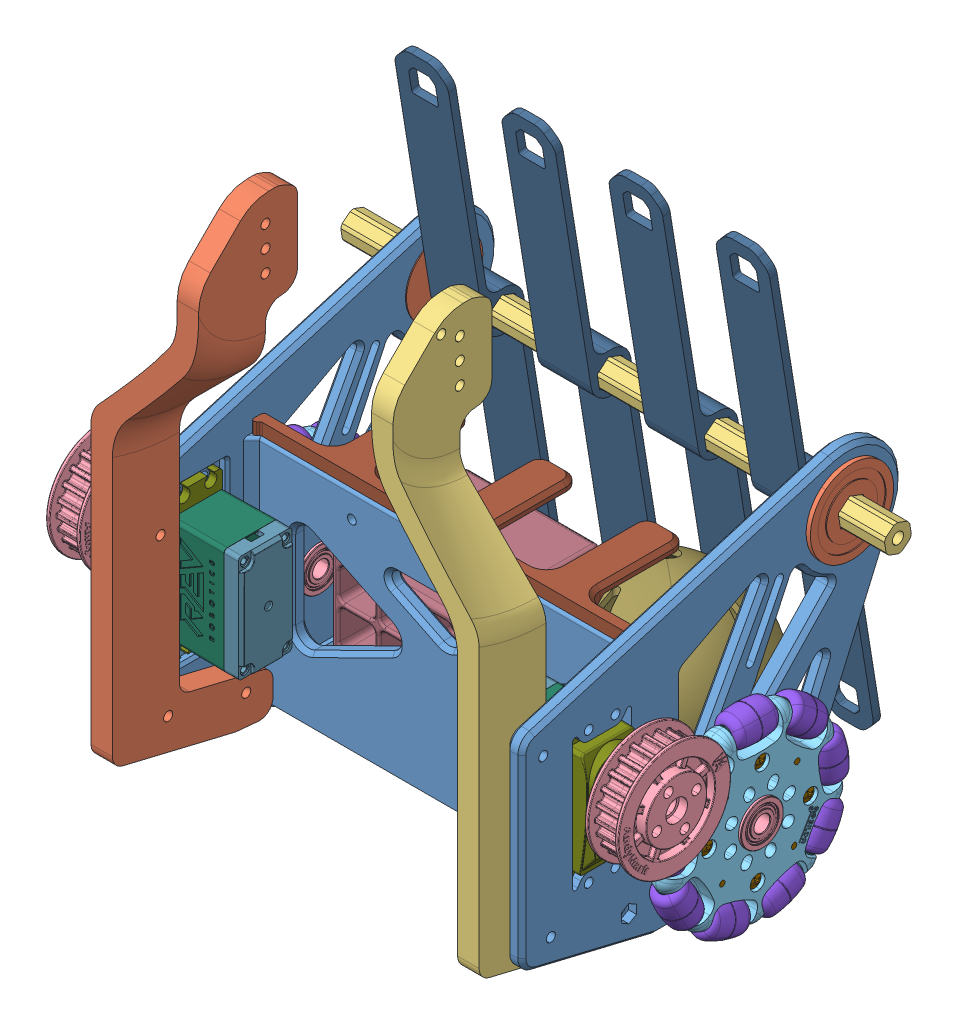
SolidWorks assembly Intake2, configuration Default. Lengths in mm.
Overall size (212.71 218.44 158.53).
113 component instances, 22 part files, 75 mates.
Components (placement in the parent):
- IntakeWide-1: IntakeWide [Default] at (-43.2378 29.5162 123.384) size (157 122.29 142.09)
- 0_375_Hex_ID_x_1_125_OD_x_0_313_WD_Flanged_Bearing_217-2735 (1).step-1: 0_375_Hex_ID_x_1_125_OD_x_0_313_WD_Flanged_Bearing_217-2735 (1).step [Default] at (101.4122 125.5162 108.384) x (0 0.631718 -0.775198) z (0 -0.775198 -0.631718) size (31.12 7.94 31.12)
- 0_375_Hex_ID_x_1_125_OD_x_0_313_WD_Flanged_Bearing_217-2735 (1).step-2: 0_375_Hex_ID_x_1_125_OD_x_0_313_WD_Flanged_Bearing_217-2735 (1).step [Default] at (-42.8878 125.5162 108.384) x (0 0.9872 0.159485) z (0 -0.159485 0.9872) size (31.12 7.94 31.12)
- 375Hex13.33in-1: 375Hex13.33in [Default] at (-330.7015 125.5132 108.3759) x (0 0.631718 -0.775198) z (-1 0 0) size (10.24 9.53 203.2)
- 1601-0014-0006.step-1: 1601-0014-0006.step [Default] at (105.8122 54.5162 155.184) x (0 -0.381849 0.924225) z (0 -0.924225 -0.381849) size (15.95 5 15.95)
- 1601-0014-0006.step-2: 1601-0014-0006.step [Default] at (-47.2878 54.5162 155.184) x (0 -1 0) z (0 0 1) size (15.95 5 15.95)
- 3604-0014-0072 assembly.STEP-1: 3604-0014-0072 assembly.STEP [Default] at (98.0385 38.1974 184.2388) x (0 -0.339821 0.94049) z (0 0.94049 0.339821) size (78.59 16.98 77.39)
  - 3604-0014-0072 wheel half.STEP-1: 3604-0014-0072 wheel half.STEP [Default] at (-32.8712 13.6737 5.4742) size (67.84 5 66.97)
  - 3604-0014-0072 wheel half.STEP-2: 3604-0014-0072 wheel half.STEP [Default] at (-32.8712 23.6737 5.4742) x (-1 0 0) z (0 0 1) size (67.84 5 66.97)
  - 3604-0014-0072 bushing.STEP-1: 3604-0014-0072 bushing.STEP [Default] at (-52.1548 18.6737 -17.5071) x (-0.130318 0.979233 -0.155307) z (-0.766044 0 0.642788) size (5.61 5.61 17.1)
  - 3604-0014-0072 shaft.STEP-1: 3604-0014-0072 shaft.STEP [Default] at (-60.0068 18.6737 -10.9185) x (0.629069 0.205497 0.749695) z (-0.132091 0.978658 -0.15742) size (3.17 20.5 3.17)
  - 3604-0014-0072 roller.STEP-1: 3604-0014-0072 roller.STEP [Default] at (-52.1548 18.6737 -17.5071) x (-0.385664 0.800009 -0.459617) z (-0.766044 0 0.642788) size (12.13 12.13 16)
  - 3604-0014-0072 shaft.STEP-2: 3604-0014-0072 shaft.STEP [Default] at (-43.1212 18.6737 -24.5258) x (0 0.205497 0.978658) z (0 0.978658 -0.205497) size (3.17 20.5 3.17)
  - 3604-0014-0072 shaft.STEP-3: 3604-0014-0072 shaft.STEP [Default] at (-21.4395 18.6737 -24.0957) x (-0.629069 0.205497 0.749695) z (0.132091 0.978658 -0.15742) size (3.17 20.5 3.17)
  - 3604-0014-0072 shaft.STEP-4: 3604-0014-0072 shaft.STEP [Default] at (-5.1069 18.6737 -9.8295) x (-0.96379 0.205497 0.169942) z (0.202375 0.978658 -0.035684) size (3.17 20.5 3.17)
  - 3604-0014-0072 shaft.STEP-5: 3604-0014-0072 shaft.STEP [Default] at (-1.7654 18.6737 11.5975) x (-0.847543 0.205497 -0.489329) z (0.177965 0.978658 0.102748) size (3.17 20.5 3.17)
  - 3604-0014-0072 shaft.STEP-6: 3604-0014-0072 shaft.STEP [Default] at (-12.9787 18.6737 30.1593) x (-0.334721 0.205497 -0.919638) z (0.070284 0.978658 0.193104) size (3.17 20.5 3.17)
  - 3604-0014-0072 shaft.STEP-7: 3604-0014-0072 shaft.STEP [Default] at (-33.4999 18.6737 37.1707) x (0.334721 0.205497 -0.919638) z (-0.070284 0.978658 0.193104) size (3.17 20.5 3.17)
  - 3604-0014-0072 shaft.STEP-8: 3604-0014-0072 shaft.STEP [Default] at (-53.727 18.6737 29.351) x (0.847543 0.205497 -0.489329) z (-0.177965 0.978658 0.102748) size (3.17 20.5 3.17)
  - 3604-0014-0072 shaft.STEP-9: 3604-0014-0072 shaft.STEP [Default] at (-64.1953 18.6737 10.3591) x (0.96379 0.205497 0.169942) z (-0.202375 0.978658 -0.035684) size (3.17 20.5 3.17)
  - 3604-0014-0072 bushing.STEP-2: 3604-0014-0072 bushing.STEP [Default] at (-32.8712 18.6737 -24.5258) x (0 0.979233 -0.202739) z (-1 0 0) size (5.61 5.61 17.1)
  - 3604-0014-0072 bushing.STEP-3: 3604-0014-0072 bushing.STEP [Default] at (-13.5876 18.6737 -17.5071) x (0.130318 0.979233 -0.155307) z (-0.766044 0 -0.642788) size (5.61 5.61 17.1)
  - 3604-0014-0072 bushing.STEP-4: 3604-0014-0072 bushing.STEP [Default] at (-3.327 18.6737 0.2648) x (0.199659 0.979233 -0.035205) z (-0.173648 0 -0.984808) size (5.61 5.61 17.1)
  - 3604-0014-0072 bushing.STEP-5: 3604-0014-0072 bushing.STEP [Default] at (-6.8904 18.6737 20.4742) x (0.175577 0.979233 0.101369) z (0.5 0 -0.866025) size (5.61 5.61 17.1)
  - 3604-0014-0072 bushing.STEP-6: 3604-0014-0072 bushing.STEP [Default] at (-22.6106 18.6737 33.665) x (0.069341 0.979233 0.190512) z (0.939693 0 -0.34202) size (5.61 5.61 17.1)
  - 3604-0014-0072 bushing.STEP-7: 3604-0014-0072 bushing.STEP [Default] at (-43.1318 18.6737 33.665) x (-0.069341 0.979233 0.190512) z (0.939693 0 0.34202) size (5.61 5.61 17.1)
  - 3604-0014-0072 bushing.STEP-8: 3604-0014-0072 bushing.STEP [Default] at (-58.852 18.6737 20.4742) x (-0.175577 0.979233 0.101369) z (0.5 0 0.866025) size (5.61 5.61 17.1)
  - 3604-0014-0072 bushing.STEP-9: 3604-0014-0072 bushing.STEP [Default] at (-62.4154 18.6737 0.2648) x (-0.199659 0.979233 -0.035205) z (-0.173648 0 0.984808) size (5.61 5.61 17.1)
  - 3604-0014-0072 roller.STEP-2: 3604-0014-0072 roller.STEP [Default] at (-32.8712 18.6737 -24.5258) x (0 0.800009 -0.599987) z (-1 0 0) size (12.13 12.13 16)
  - 3604-0014-0072 roller.STEP-3: 3604-0014-0072 roller.STEP [Default] at (-13.5876 18.6737 -17.5071) x (0.385664 0.800009 -0.459617) z (-0.766044 0 -0.642788) size (12.13 12.13 16)
  - 3604-0014-0072 roller.STEP-4: 3604-0014-0072 roller.STEP [Default] at (-3.327 18.6737 0.2648) x (0.590872 0.800009 -0.104187) z (-0.173648 0 -0.984808) size (12.13 12.13 16)
  - 3604-0014-0072 roller.STEP-5: 3604-0014-0072 roller.STEP [Default] at (-6.8904 18.6737 20.4742) x (0.519604 0.800009 0.299994) z (0.5 0 -0.866025) size (12.13 12.13 16)
  - 3604-0014-0072 roller.STEP-6: 3604-0014-0072 roller.STEP [Default] at (-22.6106 18.6737 33.665) x (0.205208 0.800009 0.563804) z (0.939693 0 -0.34202) size (12.13 12.13 16)
  - 3604-0014-0072 roller.STEP-7: 3604-0014-0072 roller.STEP [Default] at (-43.1318 18.6737 33.665) x (-0.205208 0.800009 0.563804) z (0.939693 0 0.34202) size (12.13 12.13 16)
  - 3604-0014-0072 roller.STEP-8: 3604-0014-0072 roller.STEP [Default] at (-58.852 18.6737 20.4742) x (-0.519604 0.800009 0.299994) z (0.5 0 0.866025) size (12.13 12.13 16)
  - 3604-0014-0072 roller.STEP-9: 3604-0014-0072 roller.STEP [Default] at (-62.4154 18.6737 0.2648) x (-0.590872 0.800009 -0.104187) z (-0.173648 0 0.984808) size (12.13 12.13 16)
  - 364 omni wheel screw_99461A110.STEP-1: 364 omni wheel screw_99461A110.STEP [Default] at (-40.1422 17.6737 23.0279) x (1 0 0) z (0 1 0) size (5.22 5.22 9.61)
  - 364 omni wheel screw_99461A110.STEP-2: 364 omni wheel screw_99461A110.STEP [Default] at (-50.4249 17.6737 -1.7968) x (0 0 1) z (0 1 0) size (5.22 5.22 9.61)
  - 364 omni wheel screw_99461A110.STEP-3: 364 omni wheel screw_99461A110.STEP [Default] at (-25.6002 17.6737 -12.0795) x (-1 0 0) z (0 1 0) size (5.22 5.22 9.61)
  - 364 omni wheel screw_99461A110.STEP-4: 364 omni wheel screw_99461A110.STEP [Default] at (-15.3175 17.6737 12.7452) x (0 0 -1) z (0 1 0) size (5.22 5.22 9.61)
  - 364 omni wheel screw_99461A110.STEP-5: 364 omni wheel screw_99461A110.STEP [Default] at (-25.6002 19.6737 23.0279) x (-0.837169 0 -0.546944) z (0 -1 0) size (5.22 5.22 9.61)
  - 364 omni wheel screw_99461A110.STEP-6: 364 omni wheel screw_99461A110.STEP [Default] at (-15.3175 19.6737 -1.7968) x (-0.546944 0 0.837169) z (0 -1 0) size (5.22 5.22 9.61)
  - 364 omni wheel screw_99461A110.STEP-7: 364 omni wheel screw_99461A110.STEP [Default] at (-40.1422 19.6737 -12.0795) x (0.837169 0 0.546944) z (0 -1 0) size (5.22 5.22 9.61)
  - 364 omni wheel screw_99461A110.STEP-8: 364 omni wheel screw_99461A110.STEP [Default] at (-50.4249 19.6737 12.7452) x (0.546944 0 -0.837169) z (0 -1 0) size (5.22 5.22 9.61)
- 1601-0014-0006.step-5: 1601-0014-0006.step [Default] at (117.6622 54.5162 155.184) x (0 0.825172 0.564882) z (0 0.564882 -0.825172) size (15.95 5 15.95)
- 1601-0014-0006.step-6: 1601-0014-0006.step [Default] at (115.7622 54.5162 155.184) x (0 -0.381849 0.924225) z (0 -0.924225 -0.381849) size (15.95 5 15.95)
- 1601-0014-0006.step-7: 1601-0014-0006.step [Default] at (-58.1878 54.5162 155.184) x (0 -0.381849 0.924225) z (0 -0.924225 -0.381849) size (15.95 5 15.95)
- 1601-0014-0006.step-8: 1601-0014-0006.step [Default] at (-56.2878 54.5162 155.184) x (0 0.825172 0.564882) z (0 0.564882 -0.825172) size (15.95 5 15.95)
- 3604-0014-0072 assembly.STEP-2: 3604-0014-0072 assembly.STEP [Default] at (-75.9115 38.6322 184.4787) x (0 -0.32577 0.945449) z (0 0.945449 0.32577) size (78.59 16.98 77.39)
  - 3604-0014-0072 wheel half.STEP-1: 3604-0014-0072 wheel half.STEP [Default] at (-32.8712 13.6737 5.4742) size (67.84 5 66.97)
  - 3604-0014-0072 wheel half.STEP-2: 3604-0014-0072 wheel half.STEP [Default] at (-32.8712 23.6737 5.4742) x (-1 0 0) z (0 0 1) size (67.84 5 66.97)
  - 3604-0014-0072 bushing.STEP-1: 3604-0014-0072 bushing.STEP [Default] at (-52.1548 18.6737 -17.5071) x (-0.130318 0.979233 -0.155307) z (-0.766044 0 0.642788) size (5.61 5.61 17.1)
  - 3604-0014-0072 shaft.STEP-1: 3604-0014-0072 shaft.STEP [Default] at (-60.0068 18.6737 -10.9185) x (0.629069 0.205497 0.749695) z (-0.132091 0.978658 -0.15742) size (3.17 20.5 3.17)
  - 3604-0014-0072 roller.STEP-1: 3604-0014-0072 roller.STEP [Default] at (-52.1548 18.6737 -17.5071) x (-0.385664 0.800009 -0.459617) z (-0.766044 0 0.642788) size (12.13 12.13 16)
  - 3604-0014-0072 shaft.STEP-2: 3604-0014-0072 shaft.STEP [Default] at (-43.1212 18.6737 -24.5258) x (0 0.205497 0.978658) z (0 0.978658 -0.205497) size (3.17 20.5 3.17)
  - 3604-0014-0072 shaft.STEP-3: 3604-0014-0072 shaft.STEP [Default] at (-21.4395 18.6737 -24.0957) x (-0.629069 0.205497 0.749695) z (0.132091 0.978658 -0.15742) size (3.17 20.5 3.17)
  - 3604-0014-0072 shaft.STEP-4: 3604-0014-0072 shaft.STEP [Default] at (-5.1069 18.6737 -9.8295) x (-0.96379 0.205497 0.169942) z (0.202375 0.978658 -0.035684) size (3.17 20.5 3.17)
  - 3604-0014-0072 shaft.STEP-5: 3604-0014-0072 shaft.STEP [Default] at (-1.7654 18.6737 11.5975) x (-0.847543 0.205497 -0.489329) z (0.177965 0.978658 0.102748) size (3.17 20.5 3.17)
  - 3604-0014-0072 shaft.STEP-6: 3604-0014-0072 shaft.STEP [Default] at (-12.9787 18.6737 30.1593) x (-0.334721 0.205497 -0.919638) z (0.070284 0.978658 0.193104) size (3.17 20.5 3.17)
  - 3604-0014-0072 shaft.STEP-7: 3604-0014-0072 shaft.STEP [Default] at (-33.4999 18.6737 37.1707) x (0.334721 0.205497 -0.919638) z (-0.070284 0.978658 0.193104) size (3.17 20.5 3.17)
  - 3604-0014-0072 shaft.STEP-8: 3604-0014-0072 shaft.STEP [Default] at (-53.727 18.6737 29.351) x (0.847543 0.205497 -0.489329) z (-0.177965 0.978658 0.102748) size (3.17 20.5 3.17)
  - 3604-0014-0072 shaft.STEP-9: 3604-0014-0072 shaft.STEP [Default] at (-64.1953 18.6737 10.3591) x (0.96379 0.205497 0.169942) z (-0.202375 0.978658 -0.035684) size (3.17 20.5 3.17)
  - 3604-0014-0072 bushing.STEP-2: 3604-0014-0072 bushing.STEP [Default] at (-32.8712 18.6737 -24.5258) x (0 0.979233 -0.202739) z (-1 0 0) size (5.61 5.61 17.1)
  - 3604-0014-0072 bushing.STEP-3: 3604-0014-0072 bushing.STEP [Default] at (-13.5876 18.6737 -17.5071) x (0.130318 0.979233 -0.155307) z (-0.766044 0 -0.642788) size (5.61 5.61 17.1)
  - 3604-0014-0072 bushing.STEP-4: 3604-0014-0072 bushing.STEP [Default] at (-3.327 18.6737 0.2648) x (0.199659 0.979233 -0.035205) z (-0.173648 0 -0.984808) size (5.61 5.61 17.1)
  - 3604-0014-0072 bushing.STEP-5: 3604-0014-0072 bushing.STEP [Default] at (-6.8904 18.6737 20.4742) x (0.175577 0.979233 0.101369) z (0.5 0 -0.866025) size (5.61 5.61 17.1)
  - 3604-0014-0072 bushing.STEP-6: 3604-0014-0072 bushing.STEP [Default] at (-22.6106 18.6737 33.665) x (0.069341 0.979233 0.190512) z (0.939693 0 -0.34202) size (5.61 5.61 17.1)
  - 3604-0014-0072 bushing.STEP-7: 3604-0014-0072 bushing.STEP [Default] at (-43.1318 18.6737 33.665) x (-0.069341 0.979233 0.190512) z (0.939693 0 0.34202) size (5.61 5.61 17.1)
  - 3604-0014-0072 bushing.STEP-8: 3604-0014-0072 bushing.STEP [Default] at (-58.852 18.6737 20.4742) x (-0.175577 0.979233 0.101369) z (0.5 0 0.866025) size (5.61 5.61 17.1)
  - 3604-0014-0072 bushing.STEP-9: 3604-0014-0072 bushing.STEP [Default] at (-62.4154 18.6737 0.2648) x (-0.199659 0.979233 -0.035205) z (-0.173648 0 0.984808) size (5.61 5.61 17.1)
  - 3604-0014-0072 roller.STEP-2: 3604-0014-0072 roller.STEP [Default] at (-32.8712 18.6737 -24.5258) x (0 0.800009 -0.599987) z (-1 0 0) size (12.13 12.13 16)
  - 3604-0014-0072 roller.STEP-3: 3604-0014-0072 roller.STEP [Default] at (-13.5876 18.6737 -17.5071) x (0.385664 0.800009 -0.459617) z (-0.766044 0 -0.642788) size (12.13 12.13 16)
  - 3604-0014-0072 roller.STEP-4: 3604-0014-0072 roller.STEP [Default] at (-3.327 18.6737 0.2648) x (0.590872 0.800009 -0.104187) z (-0.173648 0 -0.984808) size (12.13 12.13 16)
  - 3604-0014-0072 roller.STEP-5: 3604-0014-0072 roller.STEP [Default] at (-6.8904 18.6737 20.4742) x (0.519604 0.800009 0.299994) z (0.5 0 -0.866025) size (12.13 12.13 16)
  - 3604-0014-0072 roller.STEP-6: 3604-0014-0072 roller.STEP [Default] at (-22.6106 18.6737 33.665) x (0.205208 0.800009 0.563804) z (0.939693 0 -0.34202) size (12.13 12.13 16)
  - 3604-0014-0072 roller.STEP-7: 3604-0014-0072 roller.STEP [Default] at (-43.1318 18.6737 33.665) x (-0.205208 0.800009 0.563804) z (0.939693 0 0.34202) size (12.13 12.13 16)
  - 3604-0014-0072 roller.STEP-8: 3604-0014-0072 roller.STEP [Default] at (-58.852 18.6737 20.4742) x (-0.519604 0.800009 0.299994) z (0.5 0 0.866025) size (12.13 12.13 16)
  - 3604-0014-0072 roller.STEP-9: 3604-0014-0072 roller.STEP [Default] at (-62.4154 18.6737 0.2648) x (-0.590872 0.800009 -0.104187) z (-0.173648 0 0.984808) size (12.13 12.13 16)
  - 364 omni wheel screw_99461A110.STEP-1: 364 omni wheel screw_99461A110.STEP [Default] at (-40.1422 17.6737 23.0279) x (1 0 0) z (0 1 0) size (5.22 5.22 9.61)
  - 364 omni wheel screw_99461A110.STEP-2: 364 omni wheel screw_99461A110.STEP [Default] at (-50.4249 17.6737 -1.7968) x (0 0 1) z (0 1 0) size (5.22 5.22 9.61)
  - 364 omni wheel screw_99461A110.STEP-3: 364 omni wheel screw_99461A110.STEP [Default] at (-25.6002 17.6737 -12.0795) x (-1 0 0) z (0 1 0) size (5.22 5.22 9.61)
  - 364 omni wheel screw_99461A110.STEP-4: 364 omni wheel screw_99461A110.STEP [Default] at (-15.3175 17.6737 12.7452) x (0 0 -1) z (0 1 0) size (5.22 5.22 9.61)
  - 364 omni wheel screw_99461A110.STEP-5: 364 omni wheel screw_99461A110.STEP [Default] at (-25.6002 19.6737 23.0279) x (-0.837169 0 -0.546944) z (0 -1 0) size (5.22 5.22 9.61)
  - 364 omni wheel screw_99461A110.STEP-6: 364 omni wheel screw_99461A110.STEP [Default] at (-15.3175 19.6737 -1.7968) x (-0.546944 0 0.837169) z (0 -1 0) size (5.22 5.22 9.61)
  - 364 omni wheel screw_99461A110.STEP-7: 364 omni wheel screw_99461A110.STEP [Default] at (-40.1422 19.6737 -12.0795) x (0.837169 0 0.546944) z (0 -1 0) size (5.22 5.22 9.61)
  - 364 omni wheel screw_99461A110.STEP-8: 364 omni wheel screw_99461A110.STEP [Default] at (-50.4249 19.6737 12.7452) x (0.546944 0 -0.837169) z (0 -1 0) size (5.22 5.22 9.61)
- IntakeFlap-1: IntakeFlap [Default] at (99.2622 125.5132 108.3759) x (0 -0.9872 -0.159485) z (-1 0 0) size (180 15 20)
- IntakeFlap-2: IntakeFlap [Default] at (59.2622 125.5132 108.3759) x (0 -0.9872 -0.159485) z (-1 0 0) size (180 15 20)
- IntakeFlap-3: IntakeFlap [Default] at (19.2622 125.5132 108.3759) x (0 -0.9872 -0.159485) z (-1 0 0) size (180 15 20)
- IntakeFlap-4: IntakeFlap [Default] at (-20.7378 125.5132 108.3759) x (0 -0.9872 -0.159485) z (-1 0 0) size (180 15 20)
- Part10^Intake2-1: Part10^Intake2 [Default] at (-43.2378 110.5162 123.384) x (1 0 0) z (0 1 0) size (145 43.59 18.5) (virtual)
- am-2850 wiffle base Ball.step-1: am-2850 wiffle base Ball.step [Default] at (66.2022 65.0762 138.624) x (0.76558 0.27445 0.581863) z (-0.623857 0.095806 0.775644) size (71.12 71.12 71.12)
- ftc-2013 2in Cube.step-1: ftc-2013 2in Cube.step [Default] at (2.2547 54.9162 145.784) size (50.8 50.8 50.94)
- REV-41-1097.STEP-1: REV-41-1097.STEP [Default] at (-16.8878 77.7662 200.1841) x (0 0 1) z (1 0 0) size (24.05 54 43.73)
  - A.STEP-1: A.STEP [Default] at origin size (20.15 40.13 8.54)
  - E.STEP-1: E.STEP [Default] at origin size (20.15 40.15 20.1)
  - C.STEP-1: C.STEP [Default] at origin size (24.05 54 13.28)
  - B.STEP-1: B.STEP [Default] at origin size (9 9 4.4)
  - D.STEP-1: D.STEP [Default] at (0 -10.0526 -30.1) x (-1 0 0) z (0 0 1) size (17.21 17.2 14.7)
- REV-41-1097.STEP-2: REV-41-1097.STEP [Default] at (75.4122 77.7662 200.1835) x (0 0 -1) z (-1 0 0) size (24.05 54 43.73)
  - A.STEP-1: A.STEP [Default] at origin size (20.15 40.13 8.54)
  - E.STEP-1: E.STEP [Default] at origin size (20.15 40.15 20.1)
  - C.STEP-1: C.STEP [Default] at origin size (24.05 54 13.28)
  - B.STEP-1: B.STEP [Default] at origin size (9 9 4.4)
  - D.STEP-1: D.STEP [Default] at (0 -10.0526 -30.1) x (-1 0 0) z (0 0 1) size (17.21 17.2 14.7)
- IntakeServoHorn-1: IntakeServoHorn [Default] at (-58.5878 87.8188 200.1841) x (0 0.728708 -0.684824) z (0 0.684824 0.728708) size (25 6 25)
- IntakeServoHorn-2: IntakeServoHorn [Default] at (117.1122 87.8188 200.1835) x (0 0.059406 -0.998234) z (0 -0.998234 -0.059406) size (25 6 25)
- Part2^Intake2-1: Part2^Intake2 [Default] at (-43.2378 29.5162 123.384) x (0 0 -1) z (1 0 0) size (63.5 202.34 42.92) (virtual)
- IntakeArm2Mir-1: IntakeArm2Mir [Default] at (85.7622 29.5162 123.384) x (0 0 -1) z (1 0 0) size (60 201.86 42.92)
- am-3401+24+tooth+HTD+pulley+half+6mm+bore-1: am-3401+24+tooth+HTD+pulley+half+6mm+bore [Default] at (-70.0903 76.941 175.3595) x (-1 0 0) z (0 -0.924225 -0.381849) size (8.91 42 42)
- am-3401+24+tooth+HTD+pulley+half+6mm+bore-2: am-3401+24+tooth+HTD+pulley+half+6mm+bore [Default] at (-70.0903 60.9034 214.1769) x (1 0 0) z (0 -0.924225 -0.381849) size (8.91 42 42)
- am-3401+24+tooth+HTD+pulley+half+6mm+bore-3: am-3401+24+tooth+HTD+pulley+half+6mm+bore [Default] at (128.6147 60.3913 211.5733) x (1 0 0) z (0 -0.924225 -0.381849) size (8.91 42 42)
- am-3401+24+tooth+HTD+pulley+half+6mm+bore-4: am-3401+24+tooth+HTD+pulley+half+6mm+bore [Default] at (128.6147 76.4289 172.7559) x (-1 0 0) z (0 -0.924225 -0.381849) size (8.91 42 42)
Mates (geometry in assembly coordinates):
- Concentric1: concentric: cylinder of IntakeWide-1 through (101.7622 125.5162 108.384) axis (1 0 0) radius 14.2875; cylinder of 0_375_Hex_ID_x_1_125_OD_x_0_313_WD_Flanged_Bearing_217-2735 (1).step-1 through (101.4122 125.5162 108.384) axis (1 0 0) radius 14.2748
- Coincident1: coincident: plane of IntakeWide-1 through (107.7622 23.5162 174.184) normal (1 0 0); plane of 0_375_Hex_ID_x_1_125_OD_x_0_313_WD_Flanged_Bearing_217-2735 (1).step-1 through (107.7622 135.3442 96.3239) normal (-1 0 0)
- Concentric2: concentric: cylinder of IntakeWide-1 through (-43.2378 125.5162 108.384) axis (-1 0 0) radius 14.2875; cylinder of 0_375_Hex_ID_x_1_125_OD_x_0_313_WD_Flanged_Bearing_217-2735 (1).step-2 through (-42.8878 125.5162 108.384) axis (-1 0 0) radius 14.2748
- Coincident2: coincident: plane of IntakeWide-1 through (-49.2378 23.5162 174.184) normal (-1 0 0); plane of 0_375_Hex_ID_x_1_125_OD_x_0_313_WD_Flanged_Bearing_217-2735 (1).step-2 through (-49.2378 140.8746 110.8652) normal (1 0 0)
- Coincident3: coincident: plane of 0_375_Hex_ID_x_1_125_OD_x_0_313_WD_Flanged_Bearing_217-2735 (1).step-1 through (127.3102 123.5583 103.2359) normal (0 0.775198 0.631718); plane of 375Hex13.33in-1 through (-787.9015 123.5583 103.2359) normal (0 -0.775198 -0.631718)
- Coincident4: coincident: plane of 0_375_Hex_ID_x_1_125_OD_x_0_313_WD_Flanged_Bearing_217-2735 (1).step-2 through (-68.7858 120.0788 107.5056) normal (0 0.775198 0.631718); plane of 375Hex13.33in-1 through (-787.9015 123.5583 103.2359) normal (0 -0.775198 -0.631718)
- Coincident5: coincident: plane of 0_375_Hex_ID_x_1_125_OD_x_0_313_WD_Flanged_Bearing_217-2735 (1).step-1 through (127.3102 128.9957 104.1143) normal (0 -0.159485 0.9872); plane of 375Hex13.33in-1 through (-787.9015 128.9871 104.1129) normal (0 0.159485 -0.9872)
- Concentric3: concentric: cylinder of IntakeWide-1 through (-49.2378 54.5162 155.184) axis (1 0 0) radius 7.05; cylinder of 1601-0014-0006.step-1 through (101.7622 54.5162 155.184) axis (1 0 0) radius 7
- Coincident6: coincident: plane of IntakeWide-1 through (101.7622 29.5162 174.184) normal (-1 0 0); plane of 1601-0014-0006.step-1 through (101.7622 54.5162 155.184) normal (1 0 0)
- Coincident7: coincident: plane of IntakeWide-1 through (-43.2378 29.5162 174.184) normal (1 0 0); plane of 1601-0014-0006.step-2 through (-43.2378 54.5162 155.184) normal (-1 0 0)
- Concentric4: concentric: cylinder of IntakeWide-1 through (-49.2378 54.5162 155.184) axis (1 0 0) radius 7.05; cylinder of 1601-0014-0006.step-2 through (-43.2378 54.5162 155.184) axis (-1 0 0) radius 7
- Coincident8: coincident: circle of 3604-0014-0072 assembly.STEP-1/3604-0014-0072 wheel half.STEP-2; cylinder of 1601-0014-0006.step-5 through (121.7122 54.5162 155.184) axis (-1 0 0) radius 7
- Coincident9: coincident: plane of 3604-0014-0072 assembly.STEP-1/3604-0014-0072 wheel half.STEP-2 through (121.7122 54.5162 155.184) normal (1 0 0); plane of 1601-0014-0006.step-5 through (121.7122 54.5162 155.184) normal (-1 0 0)
- Concentric5: concentric: cylinder of 3604-0014-0072 assembly.STEP-1/3604-0014-0072 wheel half.STEP-1 through (111.7122 54.5162 155.184) axis (1 0 0) radius 7; cylinder of 1601-0014-0006.step-6 through (111.7122 54.5162 155.184) axis (1 0 0) radius 7
- Coincident10: coincident: plane of 3604-0014-0072 assembly.STEP-1/3604-0014-0072 wheel half.STEP-1 through (111.7122 54.5162 155.184) normal (-1 0 0); plane of 1601-0014-0006.step-6 through (111.7122 54.5162 155.184) normal (1 0 0)
- Concentric6: concentric: cylinder of 1601-0014-0006.step-1 through (105.8122 54.5162 155.184) axis (-1 0 0) radius 3; cylinder of 1601-0014-0006.step-5 through (117.6622 54.5162 155.184) axis (1 0 0) radius 3
- Distance2: distance = 3 mm: plane of 1601-0014-0006.step-6 through (110.7622 54.5162 155.184) normal (-1 0 0); plane of IntakeWide-1 through (107.7622 23.5162 174.184) normal (1 0 0)
- Concentric7: concentric: cylinder of 1601-0014-0006.step-7 through (-62.2378 54.5162 155.184) axis (1 0 0) radius 7; cylinder of 3604-0014-0072 assembly.STEP-2/3604-0014-0072 wheel half.STEP-1 through (-62.2378 54.5162 155.184) axis (1 0 0) radius 7
- Coincident13: coincident: cylinder of 1601-0014-0006.step-8 through (-52.2378 54.5162 155.184) axis (-1 0 0) radius 7; circle of 3604-0014-0072 assembly.STEP-2/3604-0014-0072 wheel half.STEP-2
- Coincident14: coincident: plane of 1601-0014-0006.step-8 through (-52.2378 54.5162 155.184) normal (-1 0 0); plane of 3604-0014-0072 assembly.STEP-2/3604-0014-0072 wheel half.STEP-2 through (-52.2378 54.5162 155.184) normal (1 0 0)
- Coincident15: coincident: plane of 1601-0014-0006.step-7 through (-62.2378 54.5162 155.184) normal (1 0 0); plane of 3604-0014-0072 assembly.STEP-2/3604-0014-0072 wheel half.STEP-1 through (-62.2378 54.5162 155.184) normal (-1 0 0)
- Concentric8: concentric: cylinder of 1601-0014-0006.step-2 through (-47.2878 54.5162 155.184) axis (1 0 0) radius 3; cylinder of 1601-0014-0006.step-7 through (-58.1878 54.5162 155.184) axis (-1 0 0) radius 3
- Distance3: distance = 3 mm: plane of 3604-0014-0072 assembly.STEP-2/3604-0014-0072 wheel half.STEP-2 through (-52.2378 54.5162 155.184) normal (1 0 0); plane of IntakeWide-1 through (-49.2378 23.5162 174.184) normal (-1 0 0)
- Coincident17: coincident: plane of 375Hex13.33in-1 through (-787.9015 128.9871 104.1129) normal (0 0.159485 -0.9872); plane of IntakeFlap-1 through (79.2622 128.9871 104.1129) normal (0 -0.159485 0.9872)
- Coincident18: coincident: plane of 375Hex13.33in-1 through (-787.9015 123.5583 103.2359) normal (0 -0.775198 -0.631718); plane of IntakeFlap-1 through (79.2622 123.5583 103.2359) normal (0 0.775198 0.631718)
- Coincident19: coincident: plane of 375Hex13.33in-1 through (-787.9015 122.0392 112.6389) normal (0 -0.159485 0.9872); plane of IntakeFlap-2 through (39.2622 122.0392 112.6389) normal (0 0.159485 -0.9872)
- Coincident20: coincident: plane of 375Hex13.33in-1 through (-787.9015 122.0392 112.6389) normal (0 -0.159485 0.9872); plane of IntakeFlap-3 through (-0.7378 122.0392 112.6389) normal (0 0.159485 -0.9872)
- Coincident21: coincident: plane of 375Hex13.33in-1 through (-787.9015 122.0392 112.6389) normal (0 -0.159485 0.9872); plane of IntakeFlap-4 through (-40.7378 122.0392 112.6389) normal (0 0.159485 -0.9872)
- Coincident22: coincident: plane of 375Hex13.33in-1 through (-787.9015 127.468 113.516) normal (0 0.775198 0.631718); plane of IntakeFlap-2 through (39.2622 127.468 113.516) normal (0 -0.775198 -0.631718)
- Coincident23: coincident: plane of 375Hex13.33in-1 through (-787.9015 127.468 113.516) normal (0 0.775198 0.631718); plane of IntakeFlap-3 through (-0.7378 127.468 113.516) normal (0 -0.775198 -0.631718)
- Coincident24: coincident: plane of 375Hex13.33in-1 through (-787.9015 123.5583 103.2359) normal (0 -0.775198 -0.631718); plane of IntakeFlap-4 through (-40.7378 123.5583 103.2359) normal (0 0.775198 0.631718)
- Distance4: distance = 20 mm: plane of IntakeFlap-2 through (59.2622 125.5132 108.3759) normal (1 0 0); plane of IntakeFlap-1 through (79.2622 125.5132 108.3759) normal (-1 0 0)
- Distance5: distance = 20 mm: plane of IntakeFlap-2 through (39.2622 125.5132 108.3759) normal (-1 0 0); plane of IntakeFlap-3 through (19.2622 125.5132 108.3759) normal (1 0 0)
- Distance6: distance = 20 mm: plane of IntakeFlap-4 through (-20.7378 125.5132 108.3759) normal (1 0 0); plane of IntakeFlap-3 through (-0.7378 125.5132 108.3759) normal (-1 0 0)
- Distance7: distance = 2.5 mm: plane of IntakeWide-1 through (101.7622 29.5162 174.184) normal (-1 0 0); plane of IntakeFlap-1 through (99.2622 125.5132 108.3759) normal (1 0 0)
- InPlace1: in place: plane of IntakeWide-1 through (-49.2378 110.5162 174.184) normal (0 1 0); plane of ? through (0 110.5162 0) normal (0 1 0); moOrthogonalPlaneRef_w of IntakeWide-1 through (-49.2378 110.5162 174.184) normal (0 1 0); plane of ? through (0 110.5162 0) normal (0 0 -1); plane of IntakeWide-1 through (-49.2378 110.5162 174.184) normal (0 1 0); plane of ? through (0 110.5162 0) normal (1 0 0); plane of IntakeWide-1 through (-49.2378 110.5162 174.184) normal (0 1 0); unknown of Part10^Intake2-1
- Coincident29: coincident: plane of IntakeWide-1; plane of Part10^Intake2-1
- Coincident30: coincident: moOrthogonalPlaneRef_w of IntakeWide-1 through (-43.2378 110.5162 123.384) normal (0 0 -1); plane of Part10^Intake2-1 through (-43.2378 110.5162 123.384) normal (0 0 -1)
- Coincident31: coincident: moOrthogonalPlaneRef_w of IntakeWide-1 through (-43.2378 110.5162 123.384) normal (-1 0 0); plane of Part10^Intake2-1 through (-43.2378 110.5162 123.384) normal (1 0 0)
- Tangent1: tangent: plane of IntakeWide-1 through (-43.2378 29.5162 174.184) normal (0 1 0); sphere of am-2850 wiffle base Ball.step-1
- Tangent2: tangent: plane of IntakeWide-1 through (-43.2378 29.5162 174.184) normal (0 0 -1); sphere of am-2850 wiffle base Ball.step-1
- Tangent3: tangent: plane of IntakeWide-1 through (101.7622 29.5162 174.184) normal (-1 0 0); sphere of am-2850 wiffle base Ball.step-1
- Coincident32: coincident: plane of IntakeWide-1 through (-43.2378 29.5162 174.184) normal (0 1 0); plane of ftc-2013 2in Cube.step-1 through (27.6547 29.5162 120.384) normal (0 -1 0)
- Distance8: distance = 3 mm: plane of ftc-2013 2in Cube.step-1 through (-23.1453 80.3162 171.184) normal (0 0 1); plane of IntakeWide-1 through (-43.2378 29.5162 174.184) normal (0 0 -1)
- Concentric9: concentric: cylinder of IntakeWide-1 through (-43.2378 102.5162 205.1841) axis (-1 0 0) radius 1.65; cylinder of REV-41-1097.STEP-1/C.STEP-1 through (-46.2378 102.5162 205.1841) axis (-1 0 0) radius 2.25
- Concentric10: concentric: cylinder of IntakeWide-1 through (-43.2378 102.5162 195.1835) axis (-1 0 0) radius 1.65; cylinder of REV-41-1097.STEP-1/C.STEP-1 through (-46.2378 102.5162 195.1841) axis (-1 0 0) radius 2.25
- Concentric11: concentric: cylinder of IntakeWide-1 through (101.7622 102.5162 195.1835) axis (1 0 0) radius 1.65; cylinder of REV-41-1097.STEP-2/C.STEP-1 through (104.7622 102.5162 195.1835) axis (1 0 0) radius 2.25
- Concentric12: concentric: cylinder of IntakeWide-1 through (101.7622 102.5162 205.1841) axis (1 0 0) radius 1.65; cylinder of REV-41-1097.STEP-2/C.STEP-1 through (104.7622 102.5162 205.1835) axis (1 0 0) radius 2.25
- Coincident34: coincident: plane of IntakeWide-1 through (104.7622 29.5162 123.384) normal (-1 0 0); plane of REV-41-1097.STEP-2/C.STEP-1 through (104.7622 77.7662 200.1835) normal (1 0 0)
- Concentric13: concentric: circle of REV-41-1097.STEP-1/D.STEP-1; cylinder of IntakeServoHorn-1 through (-63.0878 87.8188 200.1841) axis (1 0 0) radius 1.75
- Coincident35: coincident: plane of REV-41-1097.STEP-1/D.STEP-1 through (-60.5878 87.8188 200.1841) normal (-1 0 0); plane of IntakeServoHorn-1 through (-60.5878 87.8188 200.1841) normal (1 0 0)
- Concentric14: concentric: circle of REV-41-1097.STEP-2/D.STEP-1; cylinder of IntakeServoHorn-2 through (119.1122 87.8188 200.1835) axis (1 0 0) radius 12.5
- Coincident36: coincident: plane of REV-41-1097.STEP-2/D.STEP-1 through (119.1122 87.8188 200.1835) normal (1 0 0); plane of IntakeServoHorn-2 through (119.1122 87.8188 200.1835) normal (-1 0 0)
- BeltMate1: belt = 4.2 : 25 mm: circle of IntakeServoHorn-1; cylinder of 375Hex13.33in-1 through (126.4985 125.5132 108.3759) axis (-1 0 0) radius 2.1
- InPlace2: in place: plane of IntakeWide-1 through (-43.2378 29.5162 174.184) normal (1 0 0); plane of ? through (-43.2378 0 0) normal (1 0 0); plane of IntakeWide-1 through (-43.2378 29.5162 174.184) normal (1 0 0); plane of ? through (-43.2378 0 0) normal (0 1 0); plane of IntakeWide-1 through (-43.2378 29.5162 174.184) normal (1 0 0); plane of ? through (-43.2378 0 0) normal (0 0 -1); plane of IntakeWide-1 through (-43.2378 29.5162 174.184) normal (1 0 0); unknown of Part2^Intake2-1
- Coincident37: coincident: plane of IntakeWide-1; plane of ?
- Coincident38: coincident: moOrthogonalPlaneRef_w of IntakeWide-1 through (-43.2378 29.5162 123.384) normal (0 1 0); plane of Part2^Intake2-1 through (-43.2378 29.5162 123.384) normal (0 1 0)
- Coincident39: coincident: moOrthogonalPlaneRef_w of IntakeWide-1 through (-43.2378 29.5162 123.384) normal (0 0 1); plane of Part2^Intake2-1 through (-43.2378 29.5162 123.384) normal (0 0 -1)
- InPlace3: in place: plane of IntakeWide-1 through (-43.2378 29.5162 174.184) normal (1 0 0); plane of ? through (-43.2378 0 0) normal (1 0 0); plane of IntakeWide-1 through (-43.2378 29.5162 174.184) normal (1 0 0); plane of ? through (-43.2378 0 0) normal (0 1 0); plane of IntakeWide-1 through (-43.2378 29.5162 174.184) normal (1 0 0); plane of ? through (-43.2378 0 0) normal (0 0 -1); plane of IntakeWide-1 through (-43.2378 29.5162 174.184) normal (1 0 0); unknown of Part2^Intake2-1
- Coincident37: coincident: plane of IntakeWide-1; plane of Part2^Intake2-1
- Coincident38: coincident: moOrthogonalPlaneRef_w of IntakeWide-1 through (-43.2378 29.5162 123.384) normal (0 1 0); plane of Part2^Intake2-1 through (-43.2378 29.5162 123.384) normal (0 1 0)
- Coincident39: coincident: moOrthogonalPlaneRef_w of IntakeWide-1 through (-43.2378 29.5162 123.384) normal (0 0 1); plane of Part2^Intake2-1 through (-43.2378 29.5162 123.384) normal (0 0 -1)
- Concentric15: concentric: cylinder of IntakeWide-1 through (107.7622 42.5174 219.3556) axis (-1 0 0) radius 1.7; cylinder of IntakeArm2Mir-1 through (93.7622 42.5174 219.3556) axis (1 0 0) radius 1.7
- Concentric16: concentric: cylinder of IntakeWide-1 through (107.7622 102.5162 222.184) axis (-1 0 0) radius 1.7; cylinder of IntakeArm2Mir-1 through (93.7622 102.5162 222.184) axis (1 0 0) radius 1.7
- Coincident40: coincident: plane of IntakeWide-1 through (101.7622 29.5162 174.184) normal (-1 0 0); plane of IntakeArm2Mir-1 through (101.7622 29.5162 123.384) normal (1 0 0)
- Coincident42: coincident: plane of IntakeWide-1 through (-46.2378 29.5162 123.384) normal (1 0 0); plane of REV-41-1097.STEP-1/C.STEP-1 through (-46.2378 77.7662 200.1841) normal (-1 0 0)
- Coincident43: coincident: plane of IntakeServoHorn-1 through (-63.0878 87.8188 200.1841) normal (-1 0 0); plane of am-3401+24+tooth+HTD+pulley+half+6mm+bore-1 through (-63.0878 88.3309 202.787) normal (1 0 0)
- Concentric17: concentric: cylinder of am-3401+24+tooth+HTD+pulley+half+6mm+bore-1 through (-71.9953 88.3309 202.787) axis (1 0 0) radius 3.1; cylinder of am-3401+24+tooth+HTD+pulley+half+6mm+bore-2 through (-68.1853 88.3309 202.787) axis (-1 0 0) radius 3.1
- Coincident44: coincident: plane of am-3401+24+tooth+HTD+pulley+half+6mm+bore-1 through (-70.0903 95.0374 186.2306) normal (-1 0 0); plane of am-3401+24+tooth+HTD+pulley+half+6mm+bore-2 through (-70.0903 81.3956 219.2489) normal (1 0 0)
- Concentric18: concentric: cylinder of am-3401+24+tooth+HTD+pulley+half+6mm+bore-1 through (-71.9953 95.7256 205.8422) axis (1 0 0) radius 1.778; cylinder of am-3401+24+tooth+HTD+pulley+half+6mm+bore-2 through (-68.1853 95.7256 205.8422) axis (-1 0 0) radius 1.778
- Coincident45: coincident: plane of am-3401+24+tooth+HTD+pulley+half+6mm+bore-3 through (128.6147 80.8836 216.6454) normal (1 0 0); plane of am-3401+24+tooth+HTD+pulley+half+6mm+bore-4 through (128.6147 94.5253 183.627) normal (-1 0 0)
- Concentric19: concentric: cylinder of am-3401+24+tooth+HTD+pulley+half+6mm+bore-3 through (130.5197 87.8188 200.1835) axis (-1 0 0) radius 3.1; cylinder of am-3401+24+tooth+HTD+pulley+half+6mm+bore-4 through (126.7097 87.8188 200.1835) axis (1 0 0) radius 3.1
- Concentric20: concentric: cylinder of am-3401+24+tooth+HTD+pulley+half+6mm+bore-3 through (130.5197 95.2135 203.2386) axis (-1 0 0) radius 1.778; cylinder of am-3401+24+tooth+HTD+pulley+half+6mm+bore-4 through (126.7097 95.2135 203.2386) axis (1 0 0) radius 1.778
- Concentric21: concentric: cylinder of IntakeServoHorn-2 through (121.6122 87.8188 200.1835) axis (-1 0 0) radius 1.75; cylinder of am-3401+24+tooth+HTD+pulley+half+6mm+bore-4 through (132.4421 87.8188 200.1835) axis (1 0 0) radius 4.05
- Coincident46: coincident: plane of IntakeServoHorn-2 through (121.6122 87.8188 200.1835) normal (1 0 0); plane of am-3401+24+tooth+HTD+pulley+half+6mm+bore-3 through (121.6122 87.8188 200.1835) normal (-1 0 0)
